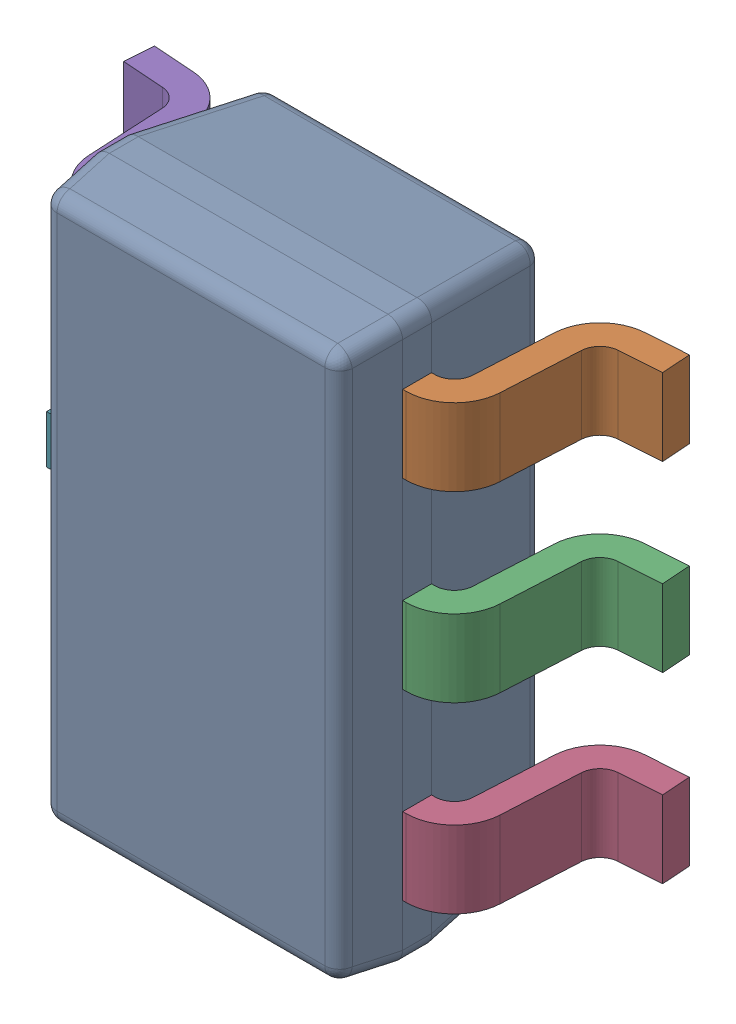
SolidWorks assembly IC18_1.step, configuration Default. Lengths in mm.
Overall size (2.8 2.9 1.2).
8 component instances, 3 part files, 0 mates.
Components (placement in the parent):
- 6348794768_1.step-3: 6348794768_1.step [Default] at (389.9005 305.0466 0) x (-1 0 0) z (0 0 1) size (2.8 2.9 1.2)
  - BODY-SOT-9_1.step-3: BODY-SOT-9_1.step [Default] at (0 0 0.9) x (0 -1 0) z (-1 0 0) size (2.9 1.1 1.6)
  - LEAD-SOT-10_1.step-13: LEAD-SOT-10_1.step [Default] at (-0.9395 -0.95 0.25) x (0 -1 0) z (-1 0 0) size (0.4 0.9 0.6)
  - LEAD-SOT-10_1.step-14: LEAD-SOT-10_1.step [Default] at (-0.9395 0 0.25) x (0 -1 0) z (-1 0 0) size (0.4 0.9 0.6)
  - LEAD-SOT-10_1.step-15: LEAD-SOT-10_1.step [Default] at (-0.9395 0.95 0.25) x (0 -1 0) z (-1 0 0) size (0.4 0.9 0.6)
  - LEAD-SOT-10_1.step-16: LEAD-SOT-10_1.step [Default] at (0.9395 -0.95 0.25) x (0 1 0) z (1 0 0) size (0.4 0.9 0.6)
  - LEAD-SOT-10_1.step-17: LEAD-SOT-10_1.step [Default] at (0.9395 0.95 0.25) x (0 1 0) z (1 0 0) size (0.4 0.9 0.6)
  - LEAD-DUMMY-11_1.step-3: LEAD-DUMMY-11_1.step [Default] at (1.05 0 0.76) x (0 -1 0) z (-1 0 0) size (0.25 0.14 0.25)
